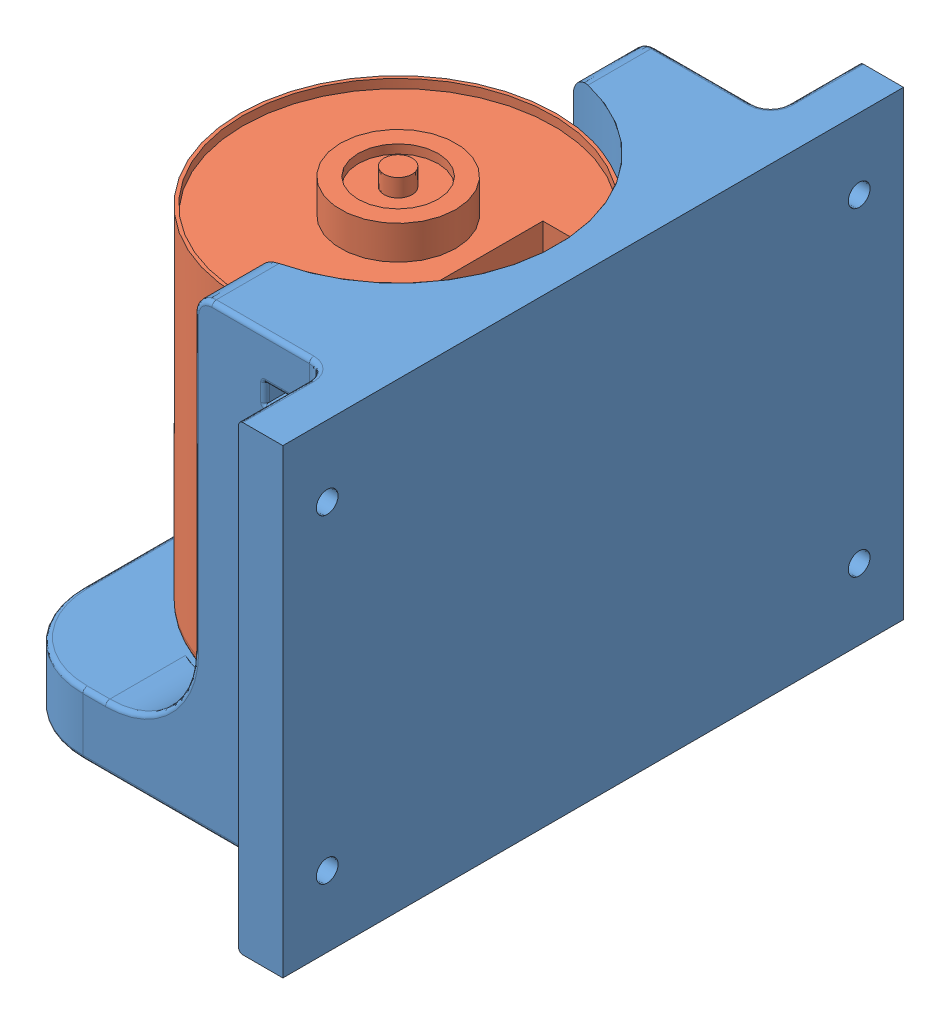
SolidWorks assembly MoteurEtSupport, configuration Défaut. Lengths in mm.
Overall size (42.55 57.9 70).
2 component instances, 2 part files, 2 mates.
Components (placement in the parent):
- SupportMoteur-1: SupportMoteur [Défaut] at (-2.7774 -21.4781 70) size (42.55 52 70)
- Moteur-1: Moteur [Défaut] at (-4.7774 18.5219 45) x (1 0 0) z (0 -1 0) size (35.75 35.75 56.7)
Mates (geometry in assembly coordinates):
- Coaxiale1: concentric: circle of SupportMoteur-1; circle of Moteur-1
- Coïncidente2: coincident: plane of SupportMoteur-1 through (-2.7774 -21.4781 70) normal (0 1 0); plane of Moteur-1 through (-4.7774 -21.4781 45) normal (0 -1 0)
